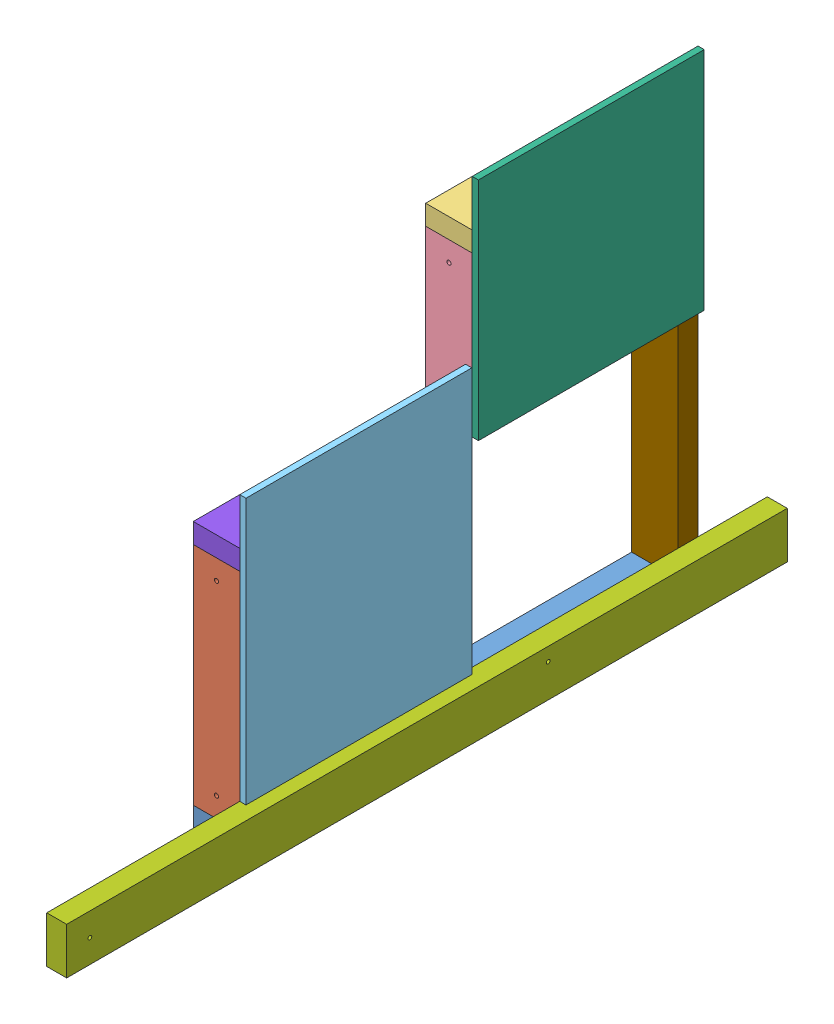
SolidWorks assembly TE-23038, configuration Default. Lengths in mm.
Overall size (127 901.7 1377.95).
9 component instances, 9 part files, 24 mates.
Components (placement in the parent):
- TE-23018-1: TE-23018 [Default] at (425.45 19.05 -0.0635) x (0 -1 0) z (0 0 1) size (38.1 88.9 876.3)
- TE-23019-1: TE-23019 [Default] at (425.45 38.1 857.1865) x (0 0 -1) z (0 1 0) size (38.1 88.9 431.8)
- TE-23023-1: TE-23023 [Default] at (425.45 793.75 -0.0635) x (0 -1 0) z (0 0 1) size (38.1 88.9 431.8)
- TE-23022-1: TE-23022 [Default] at (425.45 508 412.6865) x (0 0 1) z (0 1 0) size (38.1 88.9 266.7)
- TE-23024-1: TE-23024 [Default] at (481.8062 342.9 660.3365) x (0 0 1) z (0 -1 0) size (431.8 11.91 508)
- TE-23025-1: TE-23025 [Default] at (481.8062 685.8 215.8365) x (0 0 1) z (0 -1 0) size (431.8 11.91 431.8)
- TE-23005-1: TE-23005 [Default] at (488.95 44.45 -132.6198) size (38.1 88.9 1377.95)
- TE-23021-1: TE-23021 [Default] at (425.45 488.95 38.0365) x (0 1 0) z (0 0 1) size (38.1 88.9 838.2)
- TE-23020-1: TE-23020 [Default] at (425.45 38.1 18.9865) x (0 0 -1) z (0 1 0) size (38.1 88.9 736.6)
Mates (geometry in assembly coordinates):
- Coincident18: coincident anti-aligned: plane of Cube Shelf Long Horizontal-1 through (381 38.1 876.2365) normal (0 1 0); plane of TE-23019-1 through (425.45 38.1 857.1865) normal (0 -1 0)
- Coincident21: coincident aligned: plane of Cube Shelf Long Horizontal-1 through (469.9 38.1 876.2365) normal (1 0 0); plane of TE-23019-1 through (469.9 469.9 876.2365) normal (1 0 0)
- Distance3: distance = 88.9 mm aligned: plane of Cube Shelf Long Horizontal-1 through (381 0 876.2365) normal (0 -1 0); plane of Cube Shelf Lower Side Panel-1 through (469.9 88.9 444.4365) normal (0 -1 0)
- Coincident115: coincident anti-aligned: plane of Cube Shelf Long Horizontal-1 through (469.9 38.1 876.2365) normal (1 0 0); plane of Cone Ramp Horizontal no holes-1 through (469.9 0 1245.3302) normal (-1 0 0)
- Coincident117: coincident aligned: plane of Cube Shelf Long Horizontal-1 through (381 0 876.2365) normal (0 -1 0); plane of Cone Ramp Horizontal no holes-1 through (469.9 0 1245.3302) normal (0 -1 0)
- Coincident133: coincident anti-aligned: plane of Cube Shelf Long Horizontal-1 through (381 38.1 876.2365) normal (0 1 0); plane of TE-23020-1 through (425.45 38.1 18.9865) normal (0 -1 0)
- Coincident134: coincident aligned: plane of Cube Shelf Long Horizontal-1 through (425.45 19.05 -0.0635) normal (0 0 -1); plane of TE-23020-1 through (469.9 774.7 -0.0635) normal (0 0 -1)
- Coincident146: coincident anti-aligned: plane of TE-23019-1 through (425.45 469.9 857.1865) normal (0 1 0); plane of TE-23021-1 through (469.9 469.9 876.2365) normal (0 -1 0)
- Coincident147: coincident aligned: plane of TE-23019-1 through (469.9 469.9 876.2365) normal (0 0 1); plane of TE-23021-1 through (425.45 488.95 876.2365) normal (0 0 1)
- Coincident51: coincident aligned: plane of Cube Shelf Short Horizontal-1 through (425.45 793.75 431.7365) normal (0 0 1); plane of TE-23022-1 through (381 774.7 431.7365) normal (0 0 1)
- Coincident54: coincident aligned: plane of Cube Shelf Short Horizontal-1 through (469.9 812.8 431.7365) normal (1 0 0); plane of TE-23022-1 through (469.9 774.7 393.6365) normal (1 0 0)
- Coincident59: coincident anti-aligned: plane of Cube Shelf Short Horizontal-1 through (381 774.7 431.7365) normal (0 -1 0); plane of TE-23022-1 through (425.45 774.7 412.6865) normal (0 1 0)
- Coincident87: coincident anti-aligned: plane of Cube Shelf Short Horizontal-1 through (469.9 812.8 431.7365) normal (1 0 0); plane of TE-23025-1 through (469.9 685.8 215.8365) normal (-1 0 0)
- Coincident149: coincident aligned: plane of Cube Shelf Short Horizontal-1 through (425.45 793.75 -0.0635) normal (0 0 -1); plane of TE-23020-1 through (469.9 774.7 -0.0635) normal (0 0 -1)
- Coincident142: coincident anti-aligned: plane of TE-23022-1 through (425.45 508 412.6865) normal (0 -1 0); plane of TE-23021-1 through (469.9 508 876.2365) normal (0 1 0)
- Coincident143: coincident aligned: plane of TE-23022-1 through (381 774.7 393.6365) normal (-1 0 0); plane of TE-23021-1 through (381 469.9 876.2365) normal (-1 0 0)
- Coincident153: coincident anti-aligned: plane of TE-23024-1 through (469.9 342.9 660.3365) normal (-1 0 0); plane of TE-23021-1 through (469.9 469.9 876.2365) normal (1 0 0)
- Coincident135: coincident anti-aligned: plane of Cone Ramp Horizontal no holes-1 through (469.9 0 1245.3302) normal (-1 0 0); plane of TE-23020-1 through (469.9 774.7 38.0365) normal (1 0 0)
- Coincident144: coincident anti-aligned: plane of TE-23021-1 through (425.45 488.95 38.0365) normal (0 0 -1); plane of TE-23020-1 through (469.9 774.7 38.0365) normal (0 0 1)
- Coincident145: coincident aligned: plane of TE-23021-1 through (381 469.9 876.2365) normal (-1 0 0); plane of TE-23020-1 through (381 774.7 38.0365) normal (-1 0 0)
- Distance4: distance = 369.0938 mm aligned: plane of Cube Shelf Long Vertical-1 through (469.9 469.9 876.2365) normal (0 0 1); plane of Cone Ramp Horizontal no holes-1 through (488.95 44.45 1245.3302) normal (0 0 1)
- Coincident155: coincident aligned: plane of TE-23025-1 through (469.9 469.9 -0.0635) normal (0 -1 0); plane of TE-23021-1 through (469.9 469.9 876.2365) normal (0 -1 0)
- Coincident156: coincident aligned: plane of Cube Shelf Short Horizontal-1 through (425.45 793.75 -0.0635) normal (0 0 -1); plane of TE-23025-1 through (469.9 469.9 -0.0635) normal (0 0 -1)
- Coincident159: coincident aligned: plane of TE-23024-1 through (469.9 88.9 876.2365) normal (0 0 1); plane of TE-23021-1 through (425.45 488.95 876.2365) normal (0 0 1)
